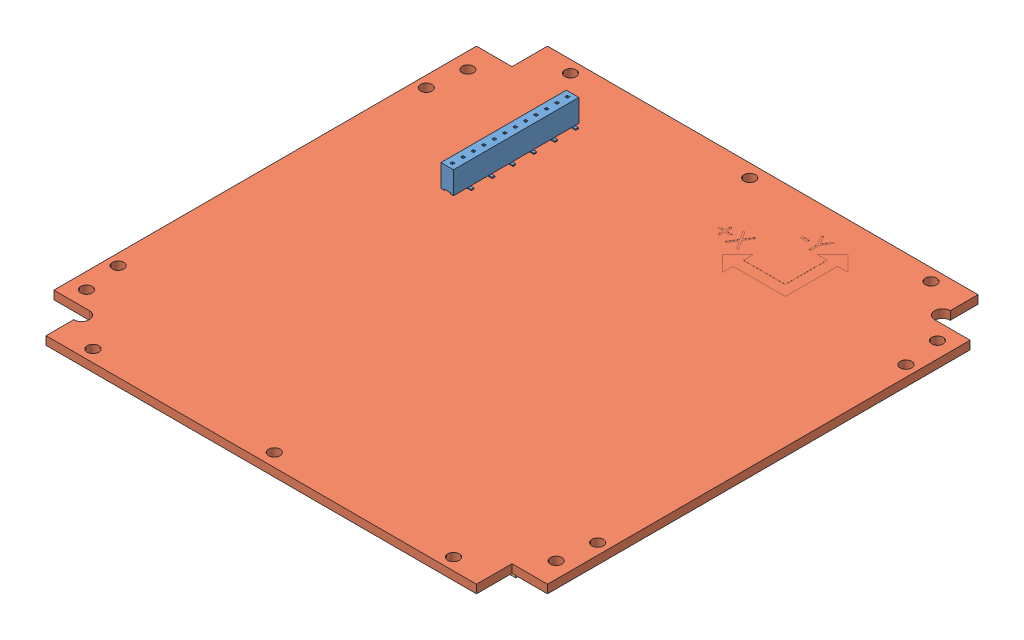
SolidWorks assembly B3_-Z_panel, configuration ﾃﾞﾌｫﾙﾄ. Lengths in mm.
Overall size (96 7.1 96).
11 component instances, 4 part files, 30 mates.
Components (placement in the parent):
- Solar panel_f-1: Solar panel_f [Default] at origin size (3.7 4.5 24)
- B3_-Z_panel-1: B3_-Z_panel [Default] at (-4.6929 -4.5 1.6444) x (0 0 1) z (1 0 0) size (96 1.6 96)
- Solar panel-1: Solar panel [Default] at (59.0669 -6.1 27.4921) x (0 0 1) z (1 0 0) size (80.15 1 40.15)
- Solar panel-2: Solar panel [Default] at (12.9169 -7.1 1.5579) x (0 0 -1) z (1 0 0) size (80.15 1 40.15)
- Solar panel_connector-1: Solar panel_connector [Default] at (22.75 -6.1 37.95) x (0 0 1) z (1 0 0) size (6.5 0.5 4)
- Solar panel_connector-2: Solar panel_connector [Default] at (22.75 -6.1 -3.05) x (0 0 1) z (1 0 0) size (6.5 0.5 4)
- Solar panel_connector-3: Solar panel_connector [Default] at (22.75 -6.1 16.95) x (0 0 1) z (1 0 0) size (6.5 0.5 4)
- Solar panel_connector-4: Solar panel_connector [Default] at (24.75 -6.1 27.7) x (0 0 1) z (1 0 0) size (6.5 0.5 4)
- Solar panel_connector-5: Solar panel_connector [Default] at (68.9 -6.1 -3.05) x (0 0 1) z (1 0 0) size (6.5 0.5 4)
- Solar panel_connector-6: Solar panel_connector [Default] at (68.9 -6.1 16.95) x (0 0 1) z (1 0 0) size (6.5 0.5 4)
- Solar panel_connector-7: Solar panel_connector [Default] at (68.9 -6.1 37.95) x (0 0 1) z (1 0 0) size (6.5 0.5 4)
Mates (geometry in assembly coordinates):
- Coincident32: coincident anti-aligned: plane of B3_-Z_panel-1 through (-4.6929 -6.1 1.6444) normal (0 -1 0); plane of Solar panel-1 through (59.0669 -6.1 27.4921) normal (0 1 0)
- Coincident33: coincident anti-aligned: plane of B3_-Z_panel-1 through (-4.6929 -6.1 1.6444) normal (0 -1 0); plane of Solar panel-2 through (12.9169 -6.1 1.5579) normal (0 1 0)
- Coincident40: coincident anti-aligned: plane of Solar panel_f-1 through (0 -4.5 0) normal (0 -1 0); plane of B3_-Z_panel-1 through (-4.6929 -4.5 1.6444) normal (0 1 0)
- Distance16: distance = 73.2 mm aligned: plane of Solar panel_f-1 through (2.4 0 -24) normal (1 0 0); plane of B3_-Z_panel-1 through (75.6 -6.1 55.2) normal (1 0 0)
- Distance17: distance = 10 mm aligned: plane of Solar panel_f-1 through (0 0 -24) normal (0 0 -1); plane of B3_-Z_panel-1 through (68.8 -6.1 -34) normal (0 0 -1)
- Distance20: distance = 7.4 mm: plane of Solar panel-2 through (22.75 -6.1 54.6) normal (0 0 1); line of B3_-Z_panel-1 through (-13.6 -6.1 62) axis (1 0 0)
- Distance23: distance = 3 mm aligned: plane of B3_-Z_panel-1 through (-20.4 -6.1 -27.2) normal (-1 0 0); plane of Solar panel-2 through (-17.4 -6.1 41.25) normal (-1 0 0)
- Coincident59: coincident aligned: plane of Solar panel-1 through (68.9 -7.1 -25.55) normal (0 0 -1); plane of Solar panel-2 through (-4.05 -6.1 -25.55) normal (0 0 -1)
- Distance27: distance = 6 mm anti-aligned: plane of Solar panel-2 through (22.75 -6.1 -25.55) normal (1 0 0); plane of Solar panel-1 through (28.75 -7.1 -12.2) normal (-1 0 0)
- 一致1: coincident anti-aligned: plane of B3_-Z_panel-1 through (-4.6929 -6.1 1.6444) normal (0 -1 0); plane of Solar panel_connector-2 through (26.25 -6.1 -4.5) normal (0 1 0)
- 一致2: coincident: plane of Solar panel-2 through (22.75 -6.1 -25.55) normal (1 0 0); line of Solar panel_connector-2 through (22.75 -6.6 -8.45) axis (0 0 -1)
- 一致3: coincident anti-aligned: plane of B3_-Z_panel-1 through (-4.6929 -6.1 1.6444) normal (0 -1 0); plane of Solar panel_connector-3 through (26.25 -6.1 15.5) normal (0 1 0)
- 一致4: coincident: plane of Solar panel-2 through (22.75 -6.1 -25.55) normal (1 0 0); line of Solar panel_connector-3 through (22.75 -6.6 15.15) axis (0 0 -1)
- 一致5: coincident anti-aligned: plane of B3_-Z_panel-1 through (-4.6929 -6.1 1.6444) normal (0 -1 0); plane of Solar panel_connector-4 through (28.25 -6.1 26.25) normal (0 1 0)
- 一致7: coincident anti-aligned: plane of B3_-Z_panel-1 through (-4.6929 -6.1 1.6444) normal (0 -1 0); plane of Solar panel_connector-5 through (72.4 -6.1 -4.5) normal (0 1 0)
- 一致8: coincident: plane of Solar panel-1 through (68.9 -7.1 54.6) normal (1 0 0); line of Solar panel_connector-5 through (68.9 -6.6 -6.65) axis (0 0 -1)
- 一致9: coincident anti-aligned: plane of B3_-Z_panel-1 through (-4.6929 -6.1 1.6444) normal (0 -1 0); plane of Solar panel_connector-6 through (72.4 -6.1 15.5) normal (0 1 0)
- 一致10: coincident: plane of Solar panel-1 through (68.9 -7.1 54.6) normal (1 0 0); line of Solar panel_connector-6 through (68.9 -6.6 13.35) axis (0 0 -1)
- 一致11: coincident anti-aligned: plane of B3_-Z_panel-1 through (-4.6929 -6.1 1.6444) normal (0 -1 0); plane of Solar panel_connector-7 through (72.4 -6.1 36.5) normal (0 1 0)
- 一致12: coincident: plane of Solar panel-1 through (68.9 -7.1 54.6) normal (1 0 0); line of Solar panel_connector-7 through (68.9 -6.6 34.35) axis (0 0 -1)
- 一致13: coincident anti-aligned: plane of B3_-Z_panel-1 through (-4.6929 -6.1 1.6444) normal (0 -1 0); plane of Solar panel_connector-1 through (26.25 -6.1 36.5) normal (0 1 0)
- 距離2: distance = 16 mm aligned: plane of Solar panel_connector-2 through (22.75 -6.6 -9.55) normal (0 0 -1); plane of Solar panel-2 through (-4.05 -6.1 -25.55) normal (0 0 -1)
- 距離3: distance = 36 mm: line of Solar panel-2 through (22.75 -7.1 -25.55) axis (-1 0 0); plane of Solar panel_connector-3 through (22.75 -6.6 10.45) normal (0 0 -1)
- 一致18: coincident: plane of Solar panel-2 through (22.75 -6.1 -25.55) normal (1 0 0); line of Solar panel_connector-1 through (22.75 -6.6 34.35) axis (0 0 -1)
- 距離4: distance = 57 mm: line of Solar panel_connector-1 through (22.75 -6.6 31.45) axis (1 0 0); plane of Solar panel-2 through (-4.05 -6.1 -25.55) normal (0 0 -1)
- 距離5: distance = 16 mm: line of Solar panel_connector-5 through (68.9 -6.6 -9.55) axis (1 0 0); plane of Solar panel-1 through (68.9 -7.1 -25.55) normal (0 0 -1)
- 距離6: distance = 36 mm aligned: plane of Solar panel-1 through (68.9 -7.1 -25.55) normal (0 0 -1); plane of Solar panel_connector-6 through (68.9 -6.6 10.45) normal (0 0 -1)
- 距離7: distance = 57 mm aligned: plane of Solar panel_connector-7 through (68.9 -6.6 31.45) normal (0 0 -1); plane of Solar panel-1 through (68.9 -7.1 -25.55) normal (0 0 -1)
- 一致23: coincident: plane of Solar panel-1 through (28.75 -7.1 -12.2) normal (-1 0 0); line of Solar panel_connector-4 through (28.75 -6.6 26.6) axis (0 0 1)
- 距離8: distance = 46.75 mm: line of Solar panel_connector-4 through (24.75 -6.6 21.2) axis (1 0 0); plane of Solar panel-1 through (68.9 -7.1 -25.55) normal (0 0 -1)
